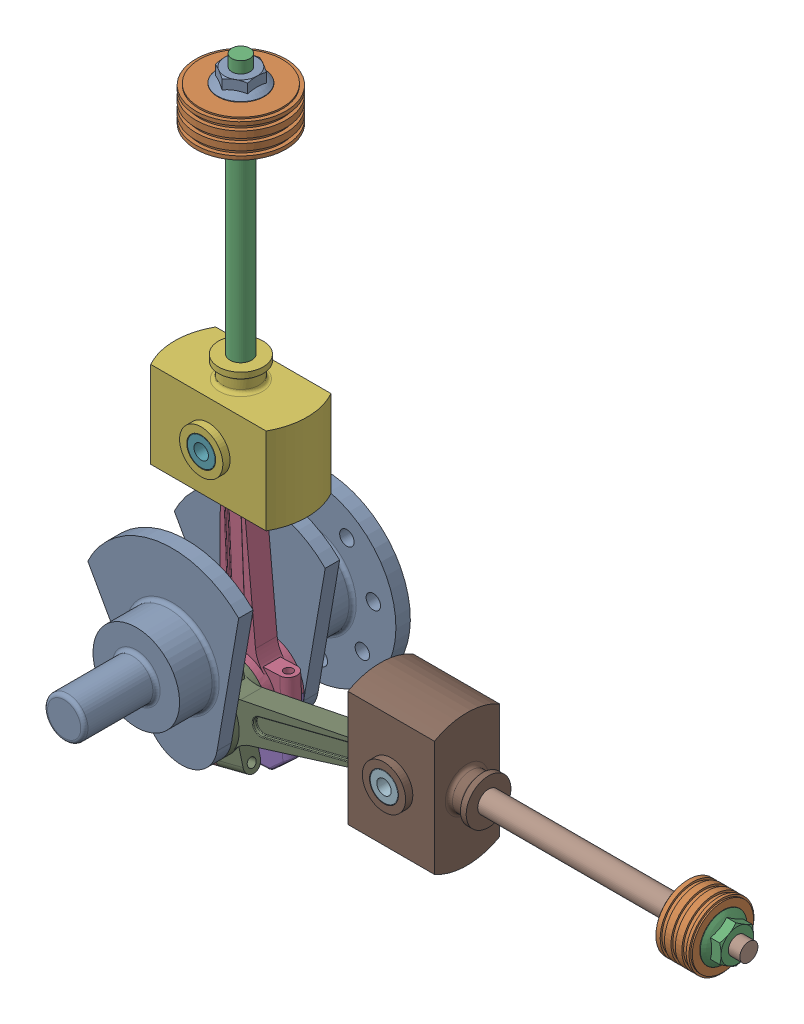
SolidWorks assembly allassemble, configuration 默认. Lengths in mm.
Overall size (894.67 835.38 467.35).
15 component instances, 9 part files, 34 mates.
Components (placement in the parent):
- crank-1: crank [默认] at (0 0 297.3468) x (0.985619 0.168981 0) z (0 0 1) size (240 255 360)
- LP-piston-1: LP-piston [默认] at (0 590.8107 222.3468) x (0.99155 0 -0.129728) z (0.129728 0 0.99155) size (125 50 125)
- pistonrod-1: pistonrod [默认] at (0 471.3107 222.3468) x (0.247258 0 -0.96895) z (0 1 0) size (30 30 411)
- connectingrod-1: connectingrod [默认] at (0 225.8107 222.3468) x (0.999107 0.042245 0) z (0 0 1) size (134 330 50)
- connectingrodnut-1: connectingrodnut [默认] at (12.6735 -73.9215 222.3468) x (-0.999107 -0.042245 0) z (0 0 1) size (134 80 50)
- crosshead-1: crosshead [默认] at (0 165.8107 222.3468) x (1 0 0) z (0 1 0) size (183.58 110 150)
- crossheadpin-1: crossheadpin [默认] at (0 225.8107 167.3468) x (1 0.000229 0) z (0.000229 -1 0) size (40 110 40)
- pistonrod-4: pistonrod [默认] at (548.9236 0 272.3468) x (0 -0.998529 -0.054224) z (1 0 0) size (30 30 411)
- connectingrod-3: connectingrod [默认] at (303.4236 0 272.3468) x (0.246405 -0.969167 0) z (0 0 1) size (134 330 50)
- connectingrodnut-3: connectingrodnut [默认] at (12.6735 -73.9215 272.3468) x (0.246405 -0.969167 0) z (0 0 -1) size (134 80 50)
- crosshead-4: crosshead [默认] at (243.4236 0 272.3468) x (0 -1 0) z (1 0 0) size (183.58 110 150)
- crossheadpin-2: crossheadpin [默认] at (303.4236 0 327.3468) x (0.804027 0.594592 0) z (-0.594592 0.804027 0) size (40 110 40)
- pistonrodnut-1: pistonrodnut [默认] at (0 640.8107 222.3468) x (1 0 0) z (0 1 0) size (64.9 64.9 20)
- HP-piston-1: HP-piston [默认] at (668.4236 0 272.3468) x (0 0.75088 0.660439) z (1 0 0) size (90 90 50)
- pistonrodnut-2: pistonrodnut [默认] at (718.4236 0 272.3468) x (0 0 -1) z (1 0 0) size (64.9 64.9 20)
Mates (geometry in assembly coordinates):
- 同心1: concentric anti-aligned: cylinder of crank-1 through (0 0 467.3468) axis (0 0 -1) radius 28
- 重合2: coincident: plane of crank-1 through (0 0 467.3468) normal (0 0 1)
- 重合3: coincident anti-aligned: plane of connectingrod-1 through (0 225.8107 247.3468) normal (0 0 1); plane of crosshead-1 through (0 225.8107 247.3468) normal (0 0 -1)
- 同心2: concentric anti-aligned: cylinder of connectingrod-1 through (0 225.8107 247.3468) axis (0 0 -1) radius 20; cylinder of crosshead-1 through (0 225.8107 177.3468) axis (0 0 1) radius 20
- 同心4: concentric anti-aligned: cylinder of crosshead-1 through (0 225.8107 177.3468) axis (0 0 1) radius 20; cylinder of crossheadpin-1 through (0 225.8107 277.3468) axis (0 0 -1) radius 20
- 重合4: coincident aligned: plane of crosshead-1 through (0 225.8107 167.3468) normal (0 0 -1); plane of crossheadpin-1 through (0 225.8107 167.3468) normal (0 0 -1)
- 同心5: concentric aligned: cylinder of connectingrod-1 through (-42.2774 -76.2449 222.3468) axis (-0.042245 0.999107 0) radius 6; cylinder of connectingrodnut-1 through (-38.8977 -156.1735 222.3468) axis (-0.042245 0.999107 0) radius 6
- 同心6: concentric aligned: cylinder of connectingrod-1 through (67.6244 -71.598 222.3468) axis (-0.042245 0.999107 0) radius 6; cylinder of connectingrodnut-1 through (71.0041 -151.5266 222.3468) axis (-0.042245 0.999107 0) radius 6
- 重合5: coincident anti-aligned: plane of connectingrod-1 through (12.6735 -73.9215 247.3468) normal (0.042245 -0.999107 0); plane of connectingrodnut-1 through (62.6289 -71.8092 247.3468) normal (-0.042245 0.999107 0)
- 重合6: coincident anti-aligned: plane of crank-1 through (0 0 197.3468) normal (0 0 1); plane of connectingrod-1 through (0 225.8107 197.3468) normal (0 0 -1)
- 同心7: concentric anti-aligned: cylinder of crank-1 through (12.6735 -73.9215 197.3468) axis (0 0 1) radius 35; cylinder of connectingrod-1 through (12.6735 -73.9215 247.3468) axis (0 0 -1) radius 35
- 同心8: concentric aligned: cone of pistonrod-1 through (0 265.8107 222.3468) axis (0 -1 0); cone of crosshead-1 through (0 270.8107 222.3468) axis (0 -1 0)
- 重合7: coincident anti-aligned: circle of 活塞杆-1; circle of 十字头-1
- 同心18: concentric aligned: cylinder of connectingrod-3 through (26.2258 -127.2256 272.3468) axis (0.969167 0.246405 0) radius 6; cylinder of connectingrodnut-3 through (-51.3075 -146.938 272.3468) axis (0.969167 0.246405 0) radius 6
- 同心19: concentric aligned: cylinder of connectingrod-3 through (-0.8787 -20.6173 272.3468) axis (0.969167 0.246405 0) radius 6; cylinder of connectingrodnut-3 through (-78.4121 -40.3297 272.3468) axis (0.969167 0.246405 0) radius 6
- 重合21: coincident anti-aligned: plane of connectingrod-3 through (12.6735 -73.9215 297.3468) normal (-0.969167 -0.246405 0); plane of connectingrodnut-3 through (0.3533 -25.4631 247.3468) normal (0.969167 0.246405 0)
- 同心20: concentric anti-aligned: cylinder of connectingrod-3 through (303.4236 0 297.3468) axis (0 0 -1) radius 20; cylinder of crosshead-4 through (303.4236 0 227.3468) axis (0 0 1) radius 20
- 重合22: coincident anti-aligned: plane of connectingrod-3 through (303.4236 0 247.3468) normal (0 0 -1); plane of crosshead-4 through (303.4236 0 247.3468) normal (0 0 1)
- 同心21: concentric aligned: cylinder of crosshead-4 through (303.4236 0 227.3468) axis (0 0 1) radius 20; cylinder of crossheadpin-2 through (303.4236 0 217.3468) axis (0 0 1) radius 20
- 重合23: coincident aligned: plane of crosshead-4 through (303.4236 0 327.3468) normal (0 0 1); plane of crossheadpin-2 through (303.4236 0 327.3468) normal (0 0 1)
- 同心22: concentric aligned: cylinder of crank-1 through (12.6735 -73.9215 197.3468) axis (0 0 1) radius 35; cylinder of connectingrodnut-3 through (12.6735 -73.9215 247.3468) axis (0 0 1) radius 35
- 重合24: coincident anti-aligned: plane of crank-1 through (0 0 297.3468) normal (0 0 -1); plane of connectingrod-3 through (303.4236 0 297.3468) normal (0 0 1)
- 同心23: concentric aligned: cone of pistonrod-4 through (343.4236 0 272.3468) axis (-1 0 0); cone of crosshead-4 through (348.4236 0 272.3468) axis (-1 0 0)
- 重合25: coincident anti-aligned: circle of 活塞杆-4; circle of 十字头-4
- 同心28: concentric anti-aligned: cylinder of crosshead-4 through (207.7178 0 272.3468) axis (-1 0 0) radius 25
- 同心29: concentric anti-aligned: cylinder of crosshead-1 through (0 130.1048 222.3468) axis (0 -1 0) radius 25
- 同心30: concentric aligned: cylinder of LP-piston-1 through (0 590.8107 222.3468) axis (0 1 0) radius 12.5; cylinder of pistonrod-1 through (0 590.8107 222.3468) axis (0 1 0) radius 12.5
- 重合31: coincident anti-aligned: plane of LP-piston-1 through (0 590.8107 222.3468) normal (0 -1 0); plane of pistonrod-1 through (0 590.8107 222.3468) normal (0 1 0)
- 重合32: coincident anti-aligned: plane of LP-piston-1 through (0 640.8107 222.3468) normal (0 1 0); plane of pistonrodnut-1 through (0 640.8107 222.3468) normal (0 -1 0)
- 同心31: concentric aligned: cylinder of pistonrod-1 through (0 590.8107 222.3468) axis (0 1 0) radius 12.5; cylinder of pistonrodnut-1 through (0 640.8107 222.3468) axis (0 1 0) radius 12.5
- 同心32: concentric anti-aligned: cylinder of pistonrod-4 through (668.4236 0 272.3468) axis (1 0 0) radius 12.5; cylinder of HP-piston-1 through (718.4236 0 272.3468) axis (-1 0 0) radius 12.5
- 重合33: coincident anti-aligned: plane of pistonrod-4 through (668.4236 0 272.3468) normal (1 0 0); plane of HP-piston-1 through (668.4236 0 272.3468) normal (-1 0 0)
- 重合34: coincident anti-aligned: plane of HP-piston-1 through (718.4236 0 272.3468) normal (1 0 0); plane of pistonrodnut-2 through (718.4236 0 272.3468) normal (-1 0 0)
- 同心33: concentric aligned: cylinder of pistonrod-4 through (668.4236 0 272.3468) axis (1 0 0) radius 12.5; cylinder of pistonrodnut-2 through (718.4236 0 272.3468) axis (1 0 0) radius 12.5
